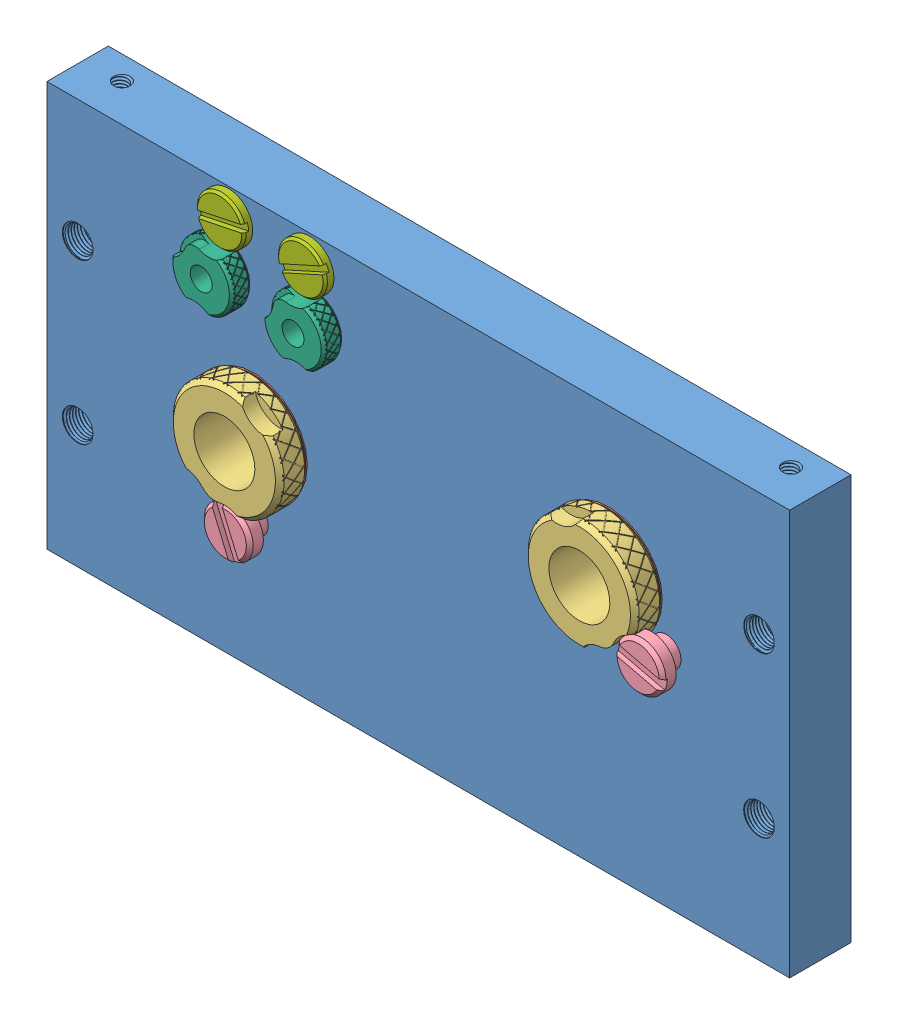
SolidWorks assembly Back Assy, configuration Default. Lengths in mm.
Overall size (242 138.45 34.93).
17 component instances, 7 part files, 12 mates.
Components (placement in the parent):
- Back-1: Back [Default] at (77.4856 183.7878 143.4707)
- 19MM Bushing-1: 19MM Bushing [Default] at (176.1432 218.5191 150.7562) x (0 0 -1) z (-0.972647 0.232289 0) size (28.57 49.02 54.37)
  - 3556N198_Sleeve for Removable Drill Bushing-1: 3556N198_Sleeve for Removable Drill Bushing [3556N198] at (-3.1895 22.8435 32.2329)
  - 8493A272_Removable Drill Bushing-1: 8493A272_Removable Drill Bushing [8493A272] at (-7.952 22.8435 32.2329) x (1 0 0) z (0 0.529453 0.848339)
  - 8496A15_Lock Screw for Removable Drill Bushings-1: 8496A15_Lock Screw for Removable Drill Bushings [8496A15] at (-10.8095 32.0046 10.6838)
- 7 mm Bushing-1: 7 mm Bushing [Default] at (-14.1275 231.0318 150.7313) x (0 0 -1) z (0.662708 -0.748878 0) size (31.75 37.33 35.17)
  - 3556N159_Sleeve for Removable Drill Bushing-1: 3556N159_Sleeve for Removable Drill Bushing [3556N159] at (-0.0394 16.7346 22.1566)
  - 8493A169_Removable Drill Bushing-1: 8493A169_Removable Drill Bushing [8493A169] at (-3.2144 16.7346 22.1566) x (1 0 0) z (0 0.635804 0.771851)
  - 8496A13_Lock Screw for Removable Drill Bushings-1: 8496A13_Lock Screw for Removable Drill Bushings [8496A13] at (-7.6467 28.9877 12.0632) x (1 0 0) z (0 -0.868859 -0.495059)
- 19MM Bushing-2: 19MM Bushing [Default] at (57.4506 163.0614 150.7562) x (0 0 -1) z (-0.391237 0.92029 0) size (28.57 49.02 54.37)
  - 3556N198_Sleeve for Removable Drill Bushing-1: 3556N198_Sleeve for Removable Drill Bushing [3556N198] at (-3.1895 22.8435 32.2329)
  - 8493A272_Removable Drill Bushing-1: 8493A272_Removable Drill Bushing [8493A272] at (-7.952 22.8435 32.2329) x (1 0 0) z (0 0.529453 0.848339)
  - 8496A15_Lock Screw for Removable Drill Bushings-1: 8496A15_Lock Screw for Removable Drill Bushings [8496A15] at (-10.8095 32.0046 10.6838)
- 7 mm Bushing-2: 7 mm Bushing [Default] at (15.2527 224.619 150.7313) x (0 0 -1) z (0.808968 -0.587853 0) size (31.75 37.33 35.17)
  - 3556N159_Sleeve for Removable Drill Bushing-1: 3556N159_Sleeve for Removable Drill Bushing [3556N159] at (-0.0394 16.7346 22.1566)
  - 8493A169_Removable Drill Bushing-1: 8493A169_Removable Drill Bushing [8493A169] at (-3.2144 16.7346 22.1566) x (1 0 0) z (0 0.635804 0.771851)
  - 8496A13_Lock Screw for Removable Drill Bushings-1: 8496A13_Lock Screw for Removable Drill Bushings [8496A13] at (-7.6467 28.9877 12.0632) x (1 0 0) z (0 -0.868859 -0.495059)
Mates (geometry in assembly coordinates):
- Concentric1: concentric aligned: cylinder of Back-1 through (43.0141 225.1319 143.4707) axis (0 0 1) radius 9.5; cylinder of 7 mm Bushing-2/3556N159_Sleeve for Removable Drill Bushing-1 through (43.0141 225.1319 163.4707) axis (0 0 1) radius 9.525
- Concentric2: concentric aligned: cylinder of Back-1 through (13.088 225.5293 143.4707) axis (0 0 1) radius 9.5; cylinder of 7 mm Bushing-1/3556N159_Sleeve for Removable Drill Bushing-1 through (13.088 225.5293 163.4707) axis (0 0 1) radius 9.525
- Coincident1: coincident anti-aligned: plane of Back-1 through (77.4856 183.7878 163.4707) normal (0 0 1); plane of 7 mm Bushing-2/8493A169_Removable Drill Bushing-1 through (42.4008 235.2336 163.4707) normal (0 0 -1)
- Coincident2: coincident anti-aligned: plane of Back-1 through (77.4856 183.7878 163.4707) normal (0 0 1); plane of 7 mm Bushing-1/8493A169_Removable Drill Bushing-1 through (14.6735 235.5247 163.4707) normal (0 0 -1)
- Concentric3: concentric aligned: cylinder of Back-1 through (139.4856 203.7878 143.4707) axis (0 0 1) radius 17.5; cylinder of 19MM Bushing-1/3556N198_Sleeve for Removable Drill Bushing-1 through (139.4856 203.7878 163.4707) axis (0 0 1) radius 17.4625
- Coincident3: coincident aligned: plane of Back-1 through (77.4856 183.7878 163.4707) normal (0 0 1); circle of 19MM Bushing-1/3556N198_Sleeve for Removable Drill Bushing-1
- Concentric4: concentric aligned: cylinder of Back-1 through (23.8172 183.7878 143.4707) axis (0 0 1) radius 17.5; cylinder of 19MM Bushing-2/3556N198_Sleeve for Removable Drill Bushing-1 through (23.8172 183.7878 163.4707) axis (0 0 1) radius 17.4625
- Coincident4: coincident aligned: plane of Back-1 through (77.4856 183.7878 163.4707) normal (0 0 1); circle of 19MM Bushing-2/3556N198_Sleeve for Removable Drill Bushing-1
- Concentric5: concentric aligned: cone of Back-1 through (23.8172 160.3722 163.4178) axis (0 0 -1); cylinder of 19MM Bushing-2/8496A15_Lock Screw for Removable Drill Bushings-1 through (23.8172 160.3722 172.6782) axis (0 0 -1) radius 7.9375
- Concentric6: concentric aligned: cone of Back-1 through (158.3173 189.8717 163.4178) axis (0 0 -1); cylinder of 19MM Bushing-1/8496A15_Lock Screw for Removable Drill Bushings-1 through (158.3173 189.8717 172.6782) axis (0 0 -1) radius 7.9375
- Concentric7: concentric aligned: cylinder of Back-1 through (42.052 240.9777 163.4707) axis (0 0 -1) radius 4.7625; cylinder of 7 mm Bushing-2/8496A13_Lock Screw for Removable Drill Bushings-1 through (42.052 240.9777 166.3155) axis (0 0 -1) radius 7.9375
- Concentric8: concentric aligned: cylinder of Back-1 through (15.5751 241.2083 163.4707) axis (0 0 -1) radius 4.7625; cylinder of 7 mm Bushing-1/8496A13_Lock Screw for Removable Drill Bushings-1 through (15.5751 241.2083 166.3155) axis (0 0 -1) radius 7.9375
